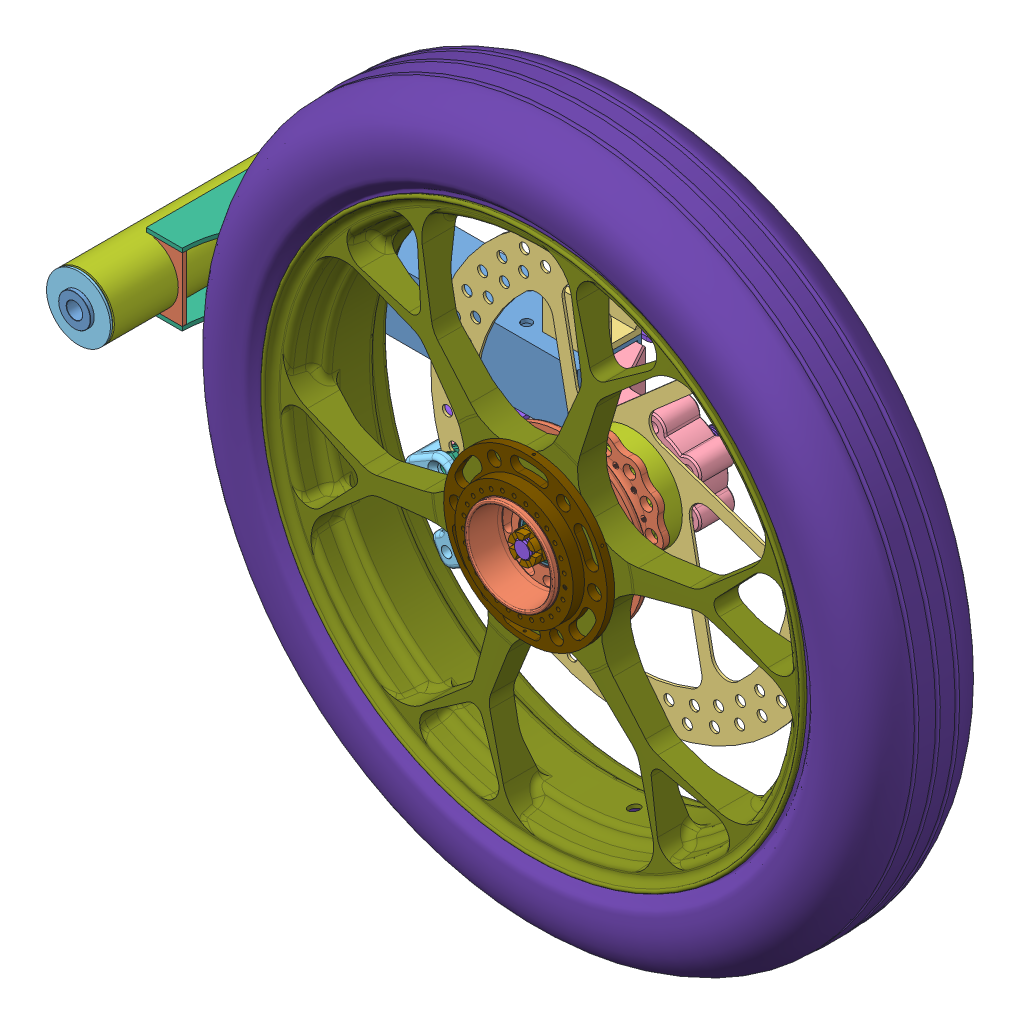
SolidWorks assembly Rear Free Spinning Assembly, configuration Default. Lengths in mm.
Overall size (695.82 635.09 190.5).
71 component instances, 29 part files, 66 mates.
Components (placement in the parent):
- 6338K423_Oil-Embedded Flanged Sleeve Bearing (1)-3: 6338K423_Oil-Embedded Flanged Sleeve Bearing (1) [6338K423] at (-275.5585 98.76 94.6109) size (25.4 25.4 19.05)
- Half Moon Bracket-2: Half Moon Bracket [Default] at (-275.5585 98.76 43.8109) x (1 0 0) z (0 -1 0) size (22.4 3.17 50.8)
- Rear Brake Bracket-2: Rear Brake Bracket [Default] at (-24.3335 128.9225 -60.9641) x (0 0 1) z (1 0 0) size (38.1 36.51 50)
- Rear Cap insert-2: Rear Cap insert [Default] at (-8.8585 76.535 -76.8391) x (0 0 1) z (-1 0 0) size (63.5 83.05 151.54)
- Rear End Cap-3: Rear End Cap [Default] at (-275.5585 98.76 100.9609) x (0 0 -1) z (0.554016 0.832506 0) size (15.88 50.8 50.8)
- Rear Gusset-2: Rear Gusset [Default] at (-50.3286 124.16 -51.4436) x (0 0 1) z (0 1 0) size (127 101.6 3.17)
- Rear Round Tube-2: Rear Round Tube [Default] at (-275.5585 98.76 97.7859) x (0 0 -1) z (1 0 0) size (177.8 50.8 50.8)
- Rear End Cap-4: Rear End Cap [Default] at (-275.5585 98.76 -83.1891) x (0 0 1) z (-0.819378 0.573254 0) size (15.88 50.8 50.8)
- 6338K423_Oil-Embedded Flanged Sleeve Bearing (1)-4: 6338K423_Oil-Embedded Flanged Sleeve Bearing (1) [6338K423] at (-275.5585 98.76 -76.8391) x (-1 0 0) z (0 0 -1) size (25.4 25.4 19.05)
- Longer Spindle_Light-1: Longer Spindle_Light [Default] at (67.3415 98.76 -13.3391) x (0 0 1) z (-0.999407 0.034445 0) size (156.55 34 30)
- 93760A127_Steel Locknut for Use with Cotter Pins-1: 93760A127_Steel Locknut for Use with Cotter Pins [93760A127] at (67.3415 98.76 91.1609) x (0.351034 0.936363 0) z (0 0 1) size (22 25.4 16.76)
- SKF_6004-2Z.stp-2: SKF_6004-2Z.stp [Default] at (67.3415 98.76 29.6609) x (0 0 -1) z (1 0 0) size (12 42 42)
  - SKF_6004-2Z_PART4.stp-1: SKF_6004-2Z_PART4.stp [Default] x (1 0 0) z (0 -0.642788 0.766044)
  - SKF_6004-2Z_PART4.stp-2: SKF_6004-2Z_PART4.stp [Default] x (1 0 0) z (0 -0.984808 0.173648)
  - SKF_6004-2Z_PART4.stp-3: SKF_6004-2Z_PART4.stp [Default] x (1 0 0) z (0 -0.866025 -0.5)
  - SKF_6004-2Z_PART4.stp-4: SKF_6004-2Z_PART4.stp [Default] x (1 0 0) z (0 -0.34202 -0.939693)
  - SKF_6004-2Z_PART4.stp-5: SKF_6004-2Z_PART4.stp [Default] x (1 0 0) z (0 0.34202 -0.939693)
  - SKF_6004-2Z_PART4.stp-6: SKF_6004-2Z_PART4.stp [Default] x (1 0 0) z (0 0.866025 -0.5)
  - SKF_6004-2Z_PART4.stp-7: SKF_6004-2Z_PART4.stp [Default] x (1 0 0) z (0 0.984808 0.173648)
  - SKF_6004-2Z_PART4.stp-8: SKF_6004-2Z_PART4.stp [Default] x (1 0 0) z (0 0.642788 0.766044)
  - SKF_6004-2Z_PART4.stp-9: SKF_6004-2Z_PART4.stp [Default] at origin
  - SKF_6004-2Z_PART3.stp-1: SKF_6004-2Z_PART3.stp [Default] x (1 0 0) z (0 -0.642788 0.766044) size (6.35 6.35 6.35)
  - SKF_6004-2Z_PART3.stp-2: SKF_6004-2Z_PART3.stp [Default] x (1 0 0) z (0 -0.984808 0.173648) size (6.35 6.35 6.35)
  - SKF_6004-2Z_PART3.stp-3: SKF_6004-2Z_PART3.stp [Default] x (1 0 0) z (0 -0.866025 -0.5) size (6.35 6.35 6.35)
  - SKF_6004-2Z_PART3.stp-4: SKF_6004-2Z_PART3.stp [Default] x (1 0 0) z (0 -0.34202 -0.939693) size (6.35 6.35 6.35)
  - SKF_6004-2Z_PART3.stp-5: SKF_6004-2Z_PART3.stp [Default] x (1 0 0) z (0 0.34202 -0.939693) size (6.35 6.35 6.35)
  - SKF_6004-2Z_PART3.stp-6: SKF_6004-2Z_PART3.stp [Default] x (1 0 0) z (0 0.866025 -0.5) size (6.35 6.35 6.35)
  - SKF_6004-2Z_PART3.stp-7: SKF_6004-2Z_PART3.stp [Default] x (1 0 0) z (0 0.984808 0.173648) size (6.35 6.35 6.35)
  - SKF_6004-2Z_PART3.stp-8: SKF_6004-2Z_PART3.stp [Default] x (1 0 0) z (0 0.642788 0.766044) size (6.35 6.35 6.35)
  - SKF_6004-2Z_PART3.stp-9: SKF_6004-2Z_PART3.stp [Default] at origin size (6.35 6.35 6.35)
  - SKF_6004-2Z_PART2.stp-1: SKF_6004-2Z_PART2.stp [Default] at origin size (12 42 42)
  - SKF_6004-2Z_PART1.stp-1: SKF_6004-2Z_PART1.stp [Default] at origin size (12 37.19 37.19)
- SKF_6003-2Z.stp-2: SKF_6003-2Z.stp [Default] at (67.3415 98.76 75.1609) x (0 0 -1) z (-0.882988 0.469396 0) size (10 35 35)
  - SKF_6003-2Z_PART4.stp-1: SKF_6003-2Z_PART4.stp [Default] x (1 0 0) z (0 -0.587785 0.809017)
  - SKF_6003-2Z_PART4.stp-2: SKF_6003-2Z_PART4.stp [Default] x (1 0 0) z (0 -0.951057 0.309017)
  - SKF_6003-2Z_PART4.stp-3: SKF_6003-2Z_PART4.stp [Default] x (1 0 0) z (0 -0.951057 -0.309017)
  - SKF_6003-2Z_PART4.stp-4: SKF_6003-2Z_PART4.stp [Default] x (1 0 0) z (0 -0.587785 -0.809017)
  - SKF_6003-2Z_PART4.stp-5: SKF_6003-2Z_PART4.stp [Default] x (1 0 0) z (0 0 -1)
  - SKF_6003-2Z_PART4.stp-6: SKF_6003-2Z_PART4.stp [Default] x (1 0 0) z (0 0.587785 -0.809017)
  - SKF_6003-2Z_PART4.stp-7: SKF_6003-2Z_PART4.stp [Default] x (1 0 0) z (0 0.951057 -0.309017)
  - SKF_6003-2Z_PART4.stp-8: SKF_6003-2Z_PART4.stp [Default] x (1 0 0) z (0 0.951057 0.309017)
  - SKF_6003-2Z_PART4.stp-9: SKF_6003-2Z_PART4.stp [Default] x (1 0 0) z (0 0.587785 0.809017)
  - SKF_6003-2Z_PART4.stp-10: SKF_6003-2Z_PART4.stp [Default] at origin
  - SKF_6003-2Z_PART3.stp-1: SKF_6003-2Z_PART3.stp [Default] x (1 0 0) z (0 -0.587785 0.809017) size (4.76 4.76 4.76)
  - SKF_6003-2Z_PART3.stp-2: SKF_6003-2Z_PART3.stp [Default] x (1 0 0) z (0 -0.951057 0.309017) size (4.76 4.76 4.76)
  - SKF_6003-2Z_PART3.stp-3: SKF_6003-2Z_PART3.stp [Default] x (1 0 0) z (0 -0.951057 -0.309017) size (4.76 4.76 4.76)
  - SKF_6003-2Z_PART3.stp-4: SKF_6003-2Z_PART3.stp [Default] x (1 0 0) z (0 -0.587785 -0.809017) size (4.76 4.76 4.76)
  - SKF_6003-2Z_PART3.stp-5: SKF_6003-2Z_PART3.stp [Default] x (1 0 0) z (0 0 -1) size (4.76 4.76 4.76)
  - SKF_6003-2Z_PART3.stp-6: SKF_6003-2Z_PART3.stp [Default] x (1 0 0) z (0 0.587785 -0.809017) size (4.76 4.76 4.76)
  - SKF_6003-2Z_PART3.stp-7: SKF_6003-2Z_PART3.stp [Default] x (1 0 0) z (0 0.951057 -0.309017) size (4.76 4.76 4.76)
  - SKF_6003-2Z_PART3.stp-8: SKF_6003-2Z_PART3.stp [Default] x (1 0 0) z (0 0.951057 0.309017) size (4.76 4.76 4.76)
  - SKF_6003-2Z_PART3.stp-9: SKF_6003-2Z_PART3.stp [Default] x (1 0 0) z (0 0.587785 0.809017) size (4.76 4.76 4.76)
  - SKF_6003-2Z_PART3.stp-10: SKF_6003-2Z_PART3.stp [Default] at origin size (4.76 4.76 4.76)
  - SKF_6003-2Z_PART2.stp-1: SKF_6003-2Z_PART2.stp [Default] at origin size (10 35 35)
  - SKF_6003-2Z_PART1.stp-1: SKF_6003-2Z_PART1.stp [Default] at origin size (10 31.2 31.2)
- Mirrorrimmachined v13.2-1: Mirrorrimmachined v13.2 [Default] at (67.3415 98.76 37.3609) x (0 0 1) z (0.757538 0.652791 0) size (93.59 431.57 431.57)
- Michelin Tire-1: Michelin Tire [Default] at (67.3415 98.76 38.6243) x (0 0 -1) z (0.988265 -0.152747 0) size (101.13 556.61 556.61)
- Nut-1: Nut [Default] at (67.3415 98.76 82.4558) x (0.057467 0.998347 0) z (0 0 -1) size (130 130 15.86)
- Rear Torque Tube-3: Rear Torque Tube [Default] at (-8.8585 124.16 -29.2141) x (0 0 -1) z (-1 0 0) size (50.8 50.8 260.35)
- 0Hub5-16-1: 0Hub5-16 [Default] at (67.3415 98.76 41.0778) x (0.896977 0.442077 0) z (-0.442077 0.896977 0) size (130 85 130)
- Large Brake Disk-1: Large Brake Disk [Default] at (67.3415 98.76 3.6609) x (0 0 -1) z (0.946854 -0.321663 0) size (2 320 320)
- Caliper Assembly-2: Caliper Assembly [Default] at (-66.2213 21.6475 -6.8199) x (0.5 -0.866025 0) z (0 0 -1) size (113.01 113.01 50.55)
  - Caliper Assembly.iam-1: Caliper Assembly.iam [Default] at origin size (113.01 113.01 50.55)
    - Caliper A v2.ipt-1: Caliper A v2.ipt [Default] x (-1 0 0) z (0 0 -1) size (69.85 44.45 25.27)
    - Caliper B v9.ipt-1: Caliper B v9.ipt [Default] at origin size (69.85 44.45 25.27)
    - MCP 554 Pads v5.ipt-1: MCP 554 Pads v5.ipt [Default] at (0.0125 -5.95 -15.4307) x (-1 0 0) z (0 0 -1) size (63.75 26 7.7)
    - MCP 554 Pads v5.ipt-2: MCP 554 Pads v5.ipt [Default] at (-0.0125 -5.95 -3.5) size (63.75 26 7.7)
    - MCP FWB caliper mounting bracket v1.ipt-1: MCP FWB caliper mounting bracket v1.ipt [Default] at (-30.8831 -83.23 3.175) x (-0.707107 0.707107 0) z (0 0 -1) size (58.07 101.75 3.36) (hidden)
- Brake Standoff-1: Brake Standoff [Default] at (67.3415 98.76 3.6609) x (-0.751995 -0.659169 0) z (0 0 1) size (80 80 19)
- Left Rear Brake Bracket-2: Left Rear Brake Bracket [Default] at (-61.0622 24.6116 -204.0699) x (-0.5 0.866025 0) z (0 0 1) size (100.49 44.43 197.25)
- Rear Gusset-3: Rear Gusset [Default] at (-50.3286 70.185 -51.4436) x (0 0 1) z (0 1 0) size (127 101.6 3.17)
Mates (geometry in assembly coordinates):
- Concentric14: concentric aligned: cylinder of Rear Round Tube-2 through (-275.5585 98.76 -80.0141) axis (0 0 1) radius 25.4; cylinder of Rear Torque Tube-2 through (-275.5585 98.76 -80.0141) axis (0 0 1) radius 25.4
- Concentric15: concentric aligned: cylinder of Rear End Cap-3 through (-275.5585 98.76 85.0859) axis (0 0 1) radius 22.225; cylinder of Rear Round Tube-2 through (-275.5585 98.76 -80.0141) axis (0 0 1) radius 22.225
- Coincident30: coincident anti-aligned: plane of Rear End Cap-3 through (-275.5585 98.76 97.7859) normal (0 0 -1); plane of Rear Round Tube-2 through (-275.5585 98.76 97.7859) normal (0 0 1)
- Concentric16: concentric anti-aligned: cylinder of Rear Round Tube-2 through (-275.5585 98.76 -80.0141) axis (0 0 1) radius 22.225; cylinder of Rear End Cap-4 through (-275.5585 98.76 -67.3141) axis (0 0 -1) radius 22.225
- Coincident31: coincident anti-aligned: plane of Rear Round Tube-2 through (-275.5585 98.76 -80.0141) normal (0 0 -1); plane of Rear End Cap-4 through (-275.5585 98.76 -80.0141) normal (0 0 1)
- Coincident32: coincident anti-aligned: circle of Rear Round Tube-2; circle of Rear Torque Tube-2
- Coincident33: coincident anti-aligned: plane of Rear Gusset-2 through (-173.9585 124.16 46.9859) normal (0 -1 0); plane of Rear Torque Tube-2 through (-269.2085 124.16 -80.0141) normal (0 1 0)
- Coincident34: coincident aligned: plane of Rear Gusset-2 through (-275.5585 127.335 -80.0141) normal (0 0 -1); plane of Rear Torque Tube-2 through (-269.2085 73.36 -80.0141) normal (0 0 -1)
- Coincident35: coincident anti-aligned: plane of Rear Gusset-2 through (-275.5585 127.335 46.9859) normal (-1 0 0); plane of Rear Round Tube-2 through (-275.5585 98.76 97.7859) normal (1 0 0)
- Concentric17: concentric anti-aligned: cylinder of Half Moon Bracket-2 through (-275.5585 98.76 46.9859) axis (0 0 -1) radius 25.4; cylinder of Rear Round Tube-2 through (-275.5585 98.76 -80.0141) axis (0 0 1) radius 25.4
- Coincident36: coincident: point of Half Moon Bracket-2; point of Rear Gusset-2
- Concentric18: concentric aligned: cylinder of Rear End Cap-4 through (-275.5585 98.76 -67.3141) axis (0 0 -1) radius 9.525; cylinder of 6338K423_Oil-Embedded Flanged Sleeve Bearing (1)-4 through (-275.5585 98.76 -67.3141) axis (0 0 -1) radius 9.5504
- Coincident37: coincident anti-aligned: plane of Rear End Cap-4 through (-275.5585 98.76 -83.1891) normal (0 0 -1); plane of 6338K423_Oil-Embedded Flanged Sleeve Bearing (1)-4 through (-275.5585 98.76 -83.1891) normal (0 0 1)
- Concentric19: concentric aligned: cylinder of 6338K423_Oil-Embedded Flanged Sleeve Bearing (1)-3 through (-275.5585 98.76 85.0859) axis (0 0 1) radius 9.5504; cylinder of Rear End Cap-3 through (-275.5585 98.76 85.0859) axis (0 0 1) radius 9.525
- Coincident39: coincident anti-aligned: plane of 6338K423_Oil-Embedded Flanged Sleeve Bearing (1)-3 through (-275.5585 98.76 100.9609) normal (0 0 -1); plane of Rear End Cap-3 through (-275.5585 98.76 100.9609) normal (0 0 1)
- Coincident40: coincident: line of Rear Brake Bracket-2 through (-49.3335 124.16 -41.9141) axis (0 0 -1); plane of Rear Torque Tube-2 through (-269.2085 124.16 -80.0141) normal (0 1 0)
- Coincident41: coincident: line of Rear Brake Bracket-2 through (-49.3335 124.16 -80.0141) axis (1 0 0); plane of Rear Torque Tube-2 through (-269.2085 73.36 -80.0141) normal (0 0 -1)
- Coincident42: coincident: point of Rear Brake Bracket-2; point of Rear Torque Tube-2
- Coincident43: coincident anti-aligned: plane of Rear Cap insert-2 through (-46.9585 120.985 -76.8391) normal (0 1 0); plane of Rear Torque Tube-2 through (-269.2085 120.985 -76.8391) normal (0 -1 0)
- Coincident44: coincident anti-aligned: plane of Rear Cap insert-2 through (-46.9585 76.535 -76.8391) normal (0 0 -1); plane of Rear Torque Tube-2 through (-269.2085 76.535 -76.8391) normal (0 0 1)
- Coincident46: coincident aligned: line of Rear Cap insert-2 through (-8.8585 77.805 -32.3891) axis (0 1 0); line of Rear Torque Tube-2 through (-8.8585 76.535 -32.3891) axis (0 1 0)
- Concentric20: concentric aligned: cylinder of Rear Cap insert-2 through (67.3415 98.76 -89.5391) axis (0 0 1) radius 10; cylinder of Longer Spindle_Light-1 through (67.3415 98.76 91.1609) axis (0 0 1) radius 10
- Coincident47: coincident anti-aligned: plane of Rear Cap insert-2 through (-8.8585 51.135 -13.3391) normal (0 0 1); plane of Longer Spindle_Light-1 through (67.6859 108.754 -13.3391) normal (0 0 -1)
- Concentric23: concentric aligned: cylinder of Longer Spindle_Light-1 through (67.3415 98.76 91.1609) axis (0 0 1) radius 12; cone of Hub-2 through (137.3345 98.76 29.6609) axis (0 0 1)
- Concentric25: concentric anti-aligned: cylinder of Longer Spindle_Light-1 through (67.3415 98.76 91.1609) axis (0 0 1) radius 8.5; cylinder of SKF_6003-2Z.stp-2/SKF_6003-2Z_PART1.stp-1 through (67.3415 98.76 25.1609) axis (0 0 -1) radius 8.5
- Coincident50: coincident anti-aligned: plane of SKF_6003-2Z.stp-2/SKF_6003-2Z_PART2.stp-1 through (60.0189 84.9854 65.1609) normal (0 0 -1); plane of Hub-2 through (145.0905 85.34 64.6609) normal (0 0 1)
- Concentric26: concentric anti-aligned: circle of 93760A127_Steel Locknut for Use with Cotter Pins-1; circle of SKF_6003-2Z.stp-2/SKF_6003-2Z_PART1.stp-1
- Coincident51: coincident anti-aligned: plane of 93760A127_Steel Locknut for Use with Cotter Pins-1 through (45.64 95.1481 75.1609) normal (0 0 -1); plane of SKF_6003-2Z.stp-2/SKF_6003-2Z_PART1.stp-1 through (61.9716 88.6586 75.1609) normal (0 0 1)
- Concentric27: concentric anti-aligned: cylinder of Hub-2 through (137.3345 98.76 -884.9499) axis (0 0 -1) radius 47; cylinder of Mirrorrimmachined v13.2-1 through (67.3415 98.76 46.4609) axis (0 0 1) radius 47.005
- Coincident52: coincident anti-aligned: plane of Hub-2 through (160.8526 58.0672 59.4689) normal (0 0 1); plane of Mirrorrimmachined v13.2-1 through (93.4531 68.4585 59.6609) normal (0 0 -1)
- Concentric28: concentric anti-aligned: cylinder of Mirrorrimmachined v13.2-1 through (67.3415 98.76 -48.1483) axis (0 0 -1) radius 192.7898; cylinder of Michelin Tire-1 through (67.3415 98.76 141.3472) axis (0 0 1) radius 203
- Concentric29: concentric aligned: circle of Mirrorrimmachined v13.2-1; cylinder of Nut-1 through (67.3415 98.76 32.3009) axis (0 0 -1) radius 65
- Coincident54: coincident anti-aligned: plane of Mirrorrimmachined v13.2-1 through (119.0298 38.7777 82.4558) normal (0 0 1); plane of Nut-1 through (69.3528 133.7021 82.4558) normal (0 0 -1)
- Concentric30: concentric anti-aligned: cylinder of Rear Round Tube-2 through (-275.5585 98.76 -80.0141) axis (0 0 1) radius 25.4; cylinder of Rear Torque Tube-3 through (-275.5585 98.76 -29.2141) axis (0 0 -1) radius 25.4
- Coincident55: coincident anti-aligned: line of Rear Gusset-2 through (-173.9585 124.16 -80.0141) axis (-1 0 0); line of Rear Torque Tube-3 through (-269.2085 124.16 -80.0141) axis (1 0 0)
- Coincident57: coincident: plane of Rear Cap insert-2 through (-46.9585 76.535 -76.8391) normal (0 0 -1); line of Rear Torque Tube-3 through (-8.8585 120.985 -76.8391) axis (0 -1 0)
- Coincident58: coincident: plane of Rear Cap insert-2 through (-46.9585 120.985 -76.8391) normal (0 1 0); line of Rear Torque Tube-3 through (-8.8585 120.985 -32.3891) axis (0 0 -1)
- Coincident60: coincident aligned: line of Rear Brake Bracket-2 through (-49.3335 124.16 -80.0141) axis (1 0 0); line of Rear Torque Tube-3 through (-269.2085 124.16 -80.0141) axis (1 0 0)
- Coincident61: coincident anti-aligned: line of Rear Brake Bracket-2 through (-8.8585 124.16 -80.0141) axis (0 0 1); line of Rear Torque Tube-3 through (-8.8585 124.16 -29.2141) axis (0 0 -1)
- Coincident62: coincident anti-aligned: plane of Rear Cap insert-2 through (-46.9585 76.535 -76.8391) normal (0 -1 0); plane of Rear Torque Tube-3 through (-269.2085 76.535 -32.3891) normal (0 1 0)
- Coincident64: coincident aligned: line of Rear Cap insert-2 through (-8.8585 77.805 -32.3891) axis (0 1 0); line of Rear Torque Tube-3 through (-8.8585 76.535 -32.3891) axis (0 1 0)
- Coincident65: coincident anti-aligned: plane of SKF_6004-2Z.stp-2/SKF_6004-2Z_PART2.stp-1 through (67.3415 119.16 29.6609) normal (0 0 1); plane of 0Hub5-16-1 through (84.384 107.1594 29.6609) normal (0 0 -1)
- Concentric31: concentric anti-aligned: cylinder of Longer Spindle_Light-1 through (67.3415 98.76 91.1609) axis (0 0 1) radius 10; cylinder of 0Hub5-16-1 through (67.3415 98.76 -884.9499) axis (0 0 -1) radius 21
- Coincident66: coincident anti-aligned: plane of Longer Spindle_Light-1 through (67.7548 110.7529 17.6609) normal (0 0 1); plane of SKF_6004-2Z.stp-2/SKF_6004-2Z_PART1.stp-1 through (67.3415 109.36 17.6609) normal (0 0 -1)
- Coincident67: coincident anti-aligned: plane of Mirrorrimmachined v13.2-1 through (93.4531 68.4585 59.6609) normal (0 0 -1); plane of 0Hub5-16-1 through (109.4994 119.5376 59.6609) normal (0 0 1)
- Concentric32: concentric aligned: cylinder of Longer Spindle_Light-1 through (67.3415 98.76 91.1609) axis (0 0 1) radius 12; cylinder of Mirrorrimmachined v13.2-1 through (67.3415 98.76 46.4609) axis (0 0 1) radius 47.005
- Concentric33: concentric anti-aligned: cylinder of 0Hub5-16-1 through (67.3415 98.76 -884.9499) axis (0 0 -1) radius 29; cylinder of Large Brake Disk-1 through (67.3415 98.76 1.6609) axis (0 0 1) radius 30
- Concentric34: concentric aligned: circle of 0Hub5-16-1; circle of Large Brake Disk-1
- Lock1: lock: unknown of Mirrorrimmachined v13.2-1; unknown of 0Hub5-16-1
- Distance1: distance = 0.75 mm anti-aligned: plane of Large Brake Disk-1 through (67.3415 98.76 3.6609) normal (0 0 1); plane of Caliper Assembly-2/Caliper Assembly.iam-1/MCP 554 Pads v5.ipt-1 through (-53.0935 10.8094 4.4109) normal (0 0 -1)
- Tangent1: tangent: plane of Caliper Assembly-2/Caliper Assembly.iam-1/Caliper A v2.ipt-1 through (-54.9728 46.6144 -6.8199) normal (0.866025 0.5 0)
- Coincident71: coincident: plane of Caliper Assembly-2 through (-66.2213 21.6475 -6.8199) normal (0.5 -0.866025 0)
- Distance5: distance = 19 mm anti-aligned: plane of 0Hub5-16-1 through (93.3538 111.5802 22.6609) normal (0 0 -1); plane of Large Brake Disk-1 through (67.3415 98.76 3.6609) normal (0 0 1)
- Lock3: lock: unknown of Mirrorrimmachined v13.2-1; unknown of Nut-1
- Coincident79: coincident anti-aligned: plane of 0Hub5-16-1 through (93.3538 111.5802 22.6609) normal (0 0 -1); plane of Brake Standoff-1 through (67.3415 98.76 22.6609) normal (0 0 1)
- Concentric35: concentric aligned: circle of 0Hub5-16-1; cylinder of Brake Standoff-1 through (67.3415 98.76 22.6609) axis (0 0 -1) radius 30
- Coincident80: coincident aligned: circle of Large Brake Disk-1; cylinder of Brake Standoff-1 through (44.9297 124.3278 22.6609) axis (0 0 -1) radius 2.625
- Coincident81: coincident anti-aligned: plane of Rear Torque Tube-3 through (-269.2085 73.36 -29.2141) normal (0 -1 0); plane of Left Rear Brake Bracket-2 through (-98.2944 73.36 -131.7797) normal (0 1 0)
- Coincident82: coincident anti-aligned: plane of Caliper Assembly-2/Caliper Assembly.iam-1/Caliper A v2.ipt-1 through (-62.0969 24.0287 -9.9949) normal (0 0 1); plane of Left Rear Brake Bracket-2 through (-62.0969 24.0287 -9.9949) normal (0 0 -1)
- Concentric36: concentric anti-aligned: circle of Caliper Assembly-2/Caliper Assembly.iam-1/Caliper A v2.ipt-1; circle of Left Rear Brake Bracket-2
- Coincident83: coincident aligned: plane of Rear Torque Tube-3 through (-269.2085 124.16 -80.0141) normal (0 0 -1); plane of Rear Gusset-3 through (-275.5585 73.36 -80.0141) normal (0 0 -1)
- Coincident84: coincident anti-aligned: plane of Half Moon Bracket-2 through (-275.5585 73.36 46.9859) normal (0 -1 0); plane of Rear Gusset-3 through (-173.9585 73.36 46.9859) normal (0 1 0)
- Coincident85: coincident aligned: plane of Rear Gusset-2 through (-275.5585 127.335 46.9859) normal (-1 0 0); plane of Rear Gusset-3 through (-275.5585 73.36 46.9859) normal (-1 0 0)
- Coincident86: coincident aligned: circle of Rear Round Tube-2; circle of Rear Torque Tube-3
- Coincident87: coincident anti-aligned: plane of SKF_6003-2Z.stp-2/SKF_6003-2Z_PART2.stp-1 through (60.0189 84.9854 65.1609) normal (0 0 -1); plane of 0Hub5-16-1 through (81.2446 105.6122 65.1609) normal (0 0 1)
- Lock4: lock: unknown of Mirrorrimmachined v13.2-1; unknown of Michelin Tire-1
